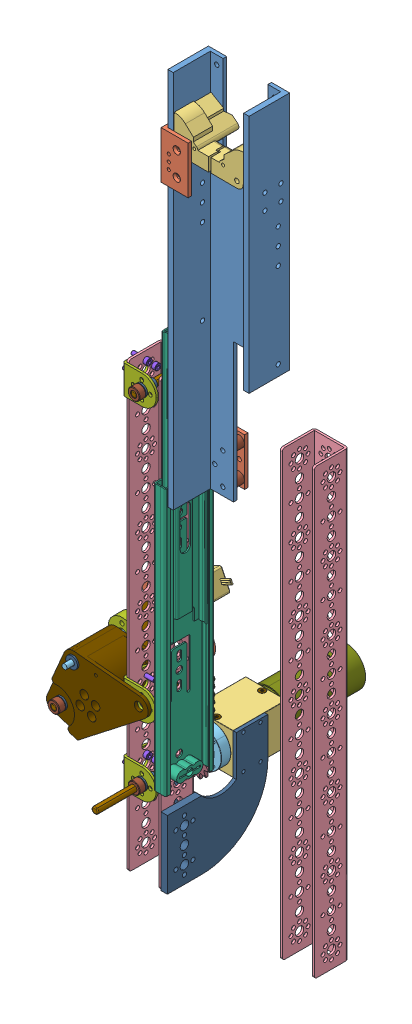
SolidWorks assembly 8699-18-203 Lander Latcher Assm, configuration Open. Lengths in mm.
Overall size (278.22 681.94 235.96).
117 component instances, 48 part files, 38 mates.
Components (placement in the parent):
- 1630T31 Machined U-Channel-1: 1630T31 Machined U-Channel [Default] at origin size (76.2 355.6 38.1)
- 8982K87 Machined Corner-1: 8982K87 Machined Corner [Default] at (-28.575 108.3632 3.175) x (0 0 -1) z (1 0 0) size (38.1 44.45 25.4)
- 8699-18-302 Lander Latcher Door-6: 8699-18-302 Lander Latcher Door [left] at (0.1845 135.2169 9.901) x (0.999933 -0.011604 0) z (0 0 1) size (32.43 32.42 38.5)
- 8699-18-302 Lander Latcher Door-7: 8699-18-302 Lander Latcher Door [right] at (0.1111 135.7078 9.901) x (-0.999976 0.006881 0) z (0 0 -1) size (32.43 32.42 38.5)
- 8699-18-204 Lander Latcher Drive-1: 8699-18-204 Lander Latcher Drive [Open] at (-72 -296.138 7.625) x (-1 0 0) z (0 0 -1) size (146.92 588.89 235.96)
  - tetrix_739069-2: tetrix_739069 [Default] at (0 192 32) x (1 0 0) z (0 1 0) size (32 32 416)
  - am-3643 NeveRest Sport, 104-1 with Motor-1: am-3643 NeveRest Sport, 104-1 with Motor [Default] at (37.7484 -95.467 21.4494) x (0 -1 0) z (0 0 1) size (48.85 48.85 145.31)
    - am-3643 NeveRest Sport, 104-1 with Motor(2)^am-3643 NeveRest Sport, 104-1 with Motor-1: am-3643 NeveRest Sport, 104-1 with Motor(2)^am-3643 NeveRest Sport, 104-1 with Motor [Default] at origin size (48.85 48.85 145.31) (virtual)
      - dv-XXXX Output Plug - 550 Sport^am-3643 NeveRest Sport, 104-1 with Motor(2)_am-3643 NeveRest Sport, 104-1 with Motor-1: dv-XXXX Output Plug - 550 Sport^am-3643 NeveRest Sport, 104-1 with Motor(2)_am-3643 NeveRest Sport, 104-1 with Motor [Default] at (30.7788 -45.9281 37.6212) x (-0.707107 -0.707107 0) z (0 0 1) size (34.54 34.54 34.87) (virtual)
        - dv-XXXX Output Plug with orbital bolt circle^dv-XXXX Output Plug - 550 Sport_am-3643 NeveRest Sport, 104-1 with Motor(2)_am-3643 NeveRest Sport, 104-1 with Motor-1: dv-XXXX Output Plug with orbital bolt circle^dv-XXXX Output Plug - 550 Sport_am-3643 NeveRest Sport, 104-1 with Motor(2)_am-3643 NeveRest Sport, 104-1 with Motor [Default] at (-7.0244 -4.5434 5.3964) size (34.54 34.54 17.78) (virtual)
        - BALL BEARING_5972K154^dv-XXXX Output Plug - 550 Sport_am-3643 NeveRest Sport, 104-1 with Motor(2)_am-3643 NeveRest Sport, 104-1 with Motor-1: BALL BEARING_5972K154^dv-XXXX Output Plug - 550 Sport_am-3643 NeveRest Sport, 104-1 with Motor(2)_am-3643 NeveRest Sport, 104-1 with Motor [Default] at (-7.0244 -4.5434 -0.8666) size (21 21 5) (virtual)
        - BALL BEARING_5972K154^dv-XXXX Output Plug - 550 Sport_am-3643 NeveRest Sport, 104-1 with Motor(2)_am-3643 NeveRest Sport, 104-1 with Motor-2: BALL BEARING_5972K154^dv-XXXX Output Plug - 550 Sport_am-3643 NeveRest Sport, 104-1 with Motor(2)_am-3643 NeveRest Sport, 104-1 with Motor [Default] at (-7.0244 -4.5434 10.1354) size (21 21 5) (virtual)
        - Nub Shaft^dv-XXXX Output Plug - 550 Sport_am-3643 NeveRest Sport, 104-1 with Motor(2)_am-3643 NeveRest Sport, 104-1 with Motor-1: Nub Shaft^dv-XXXX Output Plug - 550 Sport_am-3643 NeveRest Sport, 104-1 with Motor(2)_am-3643 NeveRest Sport, 104-1 with Motor [Default] at (-7.0244 -4.5434 20.2536) x (-0.939267 -0.343187 0) z (0.343187 -0.939267 0) size (19.05 34.87 19.05) (virtual)
      - dv-XXXX Carrier Stage 4-1 Planet, 5-1 Sun - 550 Sport^am-3643 NeveRest Sport, 104-1 with Motor(2)_am-3643 NeveRest Sport, 104-1 with Motor-1: dv-XXXX Carrier Stage 4-1 Planet, 5-1 Sun - 550 Sport^am-3643 NeveRest Sport, 104-1 with Motor(2)_am-3643 NeveRest Sport, 104-1 with Motor [Default] at (63.7059 -27.5277 100.4568) x (0.941837 -0.336071 0) z (-0.336071 -0.941837 0) size (29.23 15.47 28.59) (virtual)
        - am-2892+15T+pinion+3.2mm+bore^dv-XXXX Carrier Stage 4-1 Planet, 5-1 Sun - 550 Sport_am-3643 NeveRest Sport, 104-1 with Motor(2)_am-3643 NeveRest Sport, 104-1 with Motor-1: am-2892+15T+pinion+3.2mm+bore^dv-XXXX Carrier Stage 4-1 Planet, 5-1 Sun - 550 Sport_am-3643 NeveRest Sport, 104-1 with Motor(2)_am-3643 NeveRest Sport, 104-1 with Motor [Default] at (-25.9249 -17.3194 11.1026) x (0 -1 0) z (0.056322 0 -0.998413) size (5.31 10.12 10.18) (virtual)
        - am-2892+15T+pinion+3.2mm+bore^dv-XXXX Carrier Stage 4-1 Planet, 5-1 Sun - 550 Sport_am-3643 NeveRest Sport, 104-1 with Motor(2)_am-3643 NeveRest Sport, 104-1 with Motor-2: am-2892+15T+pinion+3.2mm+bore^dv-XXXX Carrier Stage 4-1 Planet, 5-1 Sun - 550 Sport_am-3643 NeveRest Sport, 104-1 with Motor(2)_am-3643 NeveRest Sport, 104-1 with Motor [Default] at (-16.9249 -17.3194 20.1026) x (0 -1 0) z (-0.169038 0 -0.98561) size (5.31 10.12 10.18) (virtual)
        - am-2892+15T+pinion+3.2mm+bore^dv-XXXX Carrier Stage 4-1 Planet, 5-1 Sun - 550 Sport_am-3643 NeveRest Sport, 104-1 with Motor(2)_am-3643 NeveRest Sport, 104-1 with Motor-3: am-2892+15T+pinion+3.2mm+bore^dv-XXXX Carrier Stage 4-1 Planet, 5-1 Sun - 550 Sport_am-3643 NeveRest Sport, 104-1 with Motor(2)_am-3643 NeveRest Sport, 104-1 with Motor [Default] at (-25.9249 -17.3194 29.1026) x (0 -1 0) z (-0.027474 0 -0.999623) size (5.31 10.12 10.18) (virtual)
        - am-2892+15T+pinion+3.2mm+bore^dv-XXXX Carrier Stage 4-1 Planet, 5-1 Sun - 550 Sport_am-3643 NeveRest Sport, 104-1 with Motor(2)_am-3643 NeveRest Sport, 104-1 with Motor-4: am-2892+15T+pinion+3.2mm+bore^dv-XXXX Carrier Stage 4-1 Planet, 5-1 Sun - 550 Sport_am-3643 NeveRest Sport, 104-1 with Motor(2)_am-3643 NeveRest Sport, 104-1 with Motor [Default] at (-34.9249 -17.3194 20.1026) x (0 -1 0) z (-0.064746 0 -0.997902) size (5.31 10.12 10.18) (virtual)
        - dv-XXXX - Carrier Plate 4-1 Planet, 5-1 Sun^dv-XXXX Carrier Stage 4-1 Planet, 5-1 Sun - 550 Sport_am-3643 NeveRest Sport, 104-1 with Motor(2)_am-3643 NeveRest Sport, 104-1 with Motor-1: dv-XXXX - Carrier Plate 4-1 Planet, 5-1 Sun^dv-XXXX Carrier Stage 4-1 Planet, 5-1 Sun - 550 Sport_am-3643 NeveRest Sport, 104-1 with Motor(2)_am-3643 NeveRest Sport, 104-1 with Motor [Default] at (-25.9249 -27.154 20.1026) size (25.04 10 25.04) (virtual)
        - 11T+pinion+3.2mm+bore^dv-XXXX Carrier Stage 4-1 Planet, 5-1 Sun - 550 Sport_am-3643 NeveRest Sport, 104-1 with Motor(2)_am-3643 NeveRest Sport, 104-1 with Motor-1: 11T+pinion+3.2mm+bore^dv-XXXX Carrier Stage 4-1 Planet, 5-1 Sun - 550 Sport_am-3643 NeveRest Sport, 104-1 with Motor(2)_am-3643 NeveRest Sport, 104-1 with Motor [Default] at (-25.9249 -22.6277 20.1026) x (0 -1 0) z (-0.988725 0 -0.149745) size (10 7.67 7.74) (virtual)
      - dv-XXXX Carrier Stage 5-1 Planet, 5-1 Sun^am-3643 NeveRest Sport, 104-1 with Motor(2)_am-3643 NeveRest Sport, 104-1 with Motor-1: dv-XXXX Carrier Stage 5-1 Planet, 5-1 Sun^am-3643 NeveRest Sport, 104-1 with Motor(2)_am-3643 NeveRest Sport, 104-1 with Motor [Default] at (6.8131 -34.6705 55.7021) x (-0.996841 0.079427 0) z (0.079427 0.996841 0) size (29.78 15.47 28.75) (virtual)
        - dv-XXXX - Carrier Plate 5-1 Planet, 5-1 Sun^dv-XXXX Carrier Stage 5-1 Planet, 5-1 Sun_am-3643 NeveRest Sport, 104-1 with Motor(2)_am-3643 NeveRest Sport, 104-1 with Motor-1: dv-XXXX - Carrier Plate 5-1 Planet, 5-1 Sun^dv-XXXX Carrier Stage 5-1 Planet, 5-1 Sun_am-3643 NeveRest Sport, 104-1 with Motor(2)_am-3643 NeveRest Sport, 104-1 with Motor [Default] at (-26.6144 7.6007 0.9439) size (25.04 10 25.04) (virtual)
        - 17T+pinion+3.2mm+bore^dv-XXXX Carrier Stage 5-1 Planet, 5-1 Sun_am-3643 NeveRest Sport, 104-1 with Motor(2)_am-3643 NeveRest Sport, 104-1 with Motor-1: 17T+pinion+3.2mm+bore^dv-XXXX Carrier Stage 5-1 Planet, 5-1 Sun_am-3643 NeveRest Sport, 104-1 with Motor(2)_am-3643 NeveRest Sport, 104-1 with Motor [Default] at (-35.0144 12.127 0.9439) x (0 1 0) z (-0.112997 0 0.993595) size (5.31 11.33 11.37) (virtual)
        - 17T+pinion+3.2mm+bore^dv-XXXX Carrier Stage 5-1 Planet, 5-1 Sun_am-3643 NeveRest Sport, 104-1 with Motor(2)_am-3643 NeveRest Sport, 104-1 with Motor-2: 17T+pinion+3.2mm+bore^dv-XXXX Carrier Stage 5-1 Planet, 5-1 Sun_am-3643 NeveRest Sport, 104-1 with Motor(2)_am-3643 NeveRest Sport, 104-1 with Motor [Default] at (-26.6144 12.127 9.3439) x (0 1 0) z (0.065842 0 0.99783) size (5.31 11.33 11.37) (virtual)
        - 17T+pinion+3.2mm+bore^dv-XXXX Carrier Stage 5-1 Planet, 5-1 Sun_am-3643 NeveRest Sport, 104-1 with Motor(2)_am-3643 NeveRest Sport, 104-1 with Motor-3: 17T+pinion+3.2mm+bore^dv-XXXX Carrier Stage 5-1 Planet, 5-1 Sun_am-3643 NeveRest Sport, 104-1 with Motor(2)_am-3643 NeveRest Sport, 104-1 with Motor [Default] at (-26.6144 12.127 -7.4561) x (0 1 0) z (0.038378 0 0.999263) size (5.31 11.33 11.37) (virtual)
        - 17T+pinion+3.2mm+bore^dv-XXXX Carrier Stage 5-1 Planet, 5-1 Sun_am-3643 NeveRest Sport, 104-1 with Motor(2)_am-3643 NeveRest Sport, 104-1 with Motor-4: 17T+pinion+3.2mm+bore^dv-XXXX Carrier Stage 5-1 Planet, 5-1 Sun_am-3643 NeveRest Sport, 104-1 with Motor(2)_am-3643 NeveRest Sport, 104-1 with Motor [Default] at (-18.2144 12.127 0.9439) x (0 1 0) z (0.205012 0 0.978759) size (5.31 11.33 11.37) (virtual)
        - 13T+pinion+3.2mm+bore^dv-XXXX Carrier Stage 5-1 Planet, 5-1 Sun_am-3643 NeveRest Sport, 104-1 with Motor(2)_am-3643 NeveRest Sport, 104-1 with Motor-1: 13T+pinion+3.2mm+bore^dv-XXXX Carrier Stage 5-1 Planet, 5-1 Sun_am-3643 NeveRest Sport, 104-1 with Motor(2)_am-3643 NeveRest Sport, 104-1 with Motor [Default] at (-26.6144 12.127 0.9439) x (0 -1 0) z (-0.984718 0 0.174154) size (10 8.9 8.96) (virtual)
      - dv-XXXX Carrier Stage 5-1 Planet, 0.3125 hex output^am-3643 NeveRest Sport, 104-1 with Motor(2)_am-3643 NeveRest Sport, 104-1 with Motor-1: dv-XXXX Carrier Stage 5-1 Planet, 0.3125 hex output^am-3643 NeveRest Sport, 104-1 with Motor(2)_am-3643 NeveRest Sport, 104-1 with Motor [Default] at (38.8348 -52.014 37.7173) x (0.574594 -0.818439 0) z (-0.818439 -0.574594 0) size (30.46 10 28.73) (virtual)
        - dv-XXXX - Carrier Plate 5-1 Planet, 0.3125 hex output^dv-XXXX Carrier Stage 5-1 Planet, 0.3125 hex output_am-3643 NeveRest Sport, 104-1 with Motor(2)_am-3643 NeveRest Sport, 104-1 with Motor-1: dv-XXXX - Carrier Plate 5-1 Planet, 0.3125 hex output^dv-XXXX Carrier Stage 5-1 Planet, 0.3125 hex output_am-3643 NeveRest Sport, 104-1 with Motor(2)_am-3643 NeveRest Sport, 104-1 with Motor [Default] at (-16.3468 15.5854 -4.8585) size (25.04 10 25.04) (virtual)
        - 17T+pinion+3.2mm+bore^dv-XXXX Carrier Stage 5-1 Planet, 0.3125 hex output_am-3643 NeveRest Sport, 104-1 with Motor(2)_am-3643 NeveRest Sport, 104-1 with Motor-1: 17T+pinion+3.2mm+bore^dv-XXXX Carrier Stage 5-1 Planet, 0.3125 hex output_am-3643 NeveRest Sport, 104-1 with Motor(2)_am-3643 NeveRest Sport, 104-1 with Motor [Default] at (-24.7468 20.1117 -4.8585) x (0 1 0) z (0.867721 0 0.497051) size (5.31 11.33 11.37) (virtual)
        - 17T+pinion+3.2mm+bore^dv-XXXX Carrier Stage 5-1 Planet, 0.3125 hex output_am-3643 NeveRest Sport, 104-1 with Motor(2)_am-3643 NeveRest Sport, 104-1 with Motor-2: 17T+pinion+3.2mm+bore^dv-XXXX Carrier Stage 5-1 Planet, 0.3125 hex output_am-3643 NeveRest Sport, 104-1 with Motor(2)_am-3643 NeveRest Sport, 104-1 with Motor [Default] at (-16.3468 20.1117 3.5415) x (0 1 0) z (-0.061129 0 0.99813) size (5.31 11.33 11.37) (virtual)
        - 17T+pinion+3.2mm+bore^dv-XXXX Carrier Stage 5-1 Planet, 0.3125 hex output_am-3643 NeveRest Sport, 104-1 with Motor(2)_am-3643 NeveRest Sport, 104-1 with Motor-3: 17T+pinion+3.2mm+bore^dv-XXXX Carrier Stage 5-1 Planet, 0.3125 hex output_am-3643 NeveRest Sport, 104-1 with Motor(2)_am-3643 NeveRest Sport, 104-1 with Motor [Default] at (-16.3468 20.1117 -13.2585) x (0 1 0) z (0.038378 0 0.999263) size (5.31 11.33 11.37) (virtual)
        - 17T+pinion+3.2mm+bore^dv-XXXX Carrier Stage 5-1 Planet, 0.3125 hex output_am-3643 NeveRest Sport, 104-1 with Motor(2)_am-3643 NeveRest Sport, 104-1 with Motor-4: 17T+pinion+3.2mm+bore^dv-XXXX Carrier Stage 5-1 Planet, 0.3125 hex output_am-3643 NeveRest Sport, 104-1 with Motor(2)_am-3643 NeveRest Sport, 104-1 with Motor [Default] at (-7.9468 20.1117 -4.8585) x (0 1 0) z (0.040503 0 0.999179) size (5.31 11.33 11.37) (virtual)
      - neveRest+15T+pinion^am-3643 NeveRest Sport, 104-1 with Motor(2)_am-3643 NeveRest Sport, 104-1 with Motor-1: neveRest+15T+pinion^am-3643 NeveRest Sport, 104-1 with Motor(2)_am-3643 NeveRest Sport, 104-1 with Motor [Default] at (-29.3619 -57.8483 143.121) x (-0.999543 0.030232 0) z (0 0 -1) size (38 38 89.79) (virtual)
        - am-3104 NeveRest Motor^neveRest+15T+pinion_am-3643 NeveRest Sport, 104-1 with Motor(2)_am-3643 NeveRest Sport, 104-1 with Motor-1: am-3104 NeveRest Motor^neveRest+15T+pinion_am-3643 NeveRest Sport, 104-1 with Motor(2)_am-3643 NeveRest Sport, 104-1 with Motor [Default] at (-61.259 21.9619 50.009) size (38 38 85.19) (virtual)
        - 15T+pinion+3.2mm+bore+motor^neveRest+15T+pinion_am-3643 NeveRest Sport, 104-1 with Motor(2)_am-3643 NeveRest Sport, 104-1 with Motor-1: 15T+pinion+3.2mm+bore+motor^neveRest+15T+pinion_am-3643 NeveRest Sport, 104-1 with Motor(2)_am-3643 NeveRest Sport, 104-1 with Motor [Default] at (-61.259 21.9619 54.7947) x (0 0 1) z (-0.930076 -0.367368 0) size (9.81 10.12 10.18) (virtual)
      - 91294A126_BLACK ALLOY STEEL FLAT-HEAD SOCKET CAP SCREW_91294A126^am-3643 NeveRest Sport, 104-1 with Motor(2)_am-3643 NeveRest Sport, 104-1 with Motor-1: 91294A126_BLACK ALLOY STEEL FLAT-HEAD SOCKET CAP SCREW_91294A126^am-3643 NeveRest Sport, 104-1 with Motor(2)_am-3643 NeveRest Sport, 104-1 with Motor [Default] at (13.433 -37.7484 46.9556) x (0 0 1) z (-1 0 0) size (6 6 6.01) (virtual)
      - Thrust Washer^am-3643 NeveRest Sport, 104-1 with Motor(2)_am-3643 NeveRest Sport, 104-1 with Motor-1: Thrust Washer^am-3643 NeveRest Sport, 104-1 with Motor(2)_am-3643 NeveRest Sport, 104-1 with Motor [Default] at (32.533 -37.7484 84.9184) x (0.422278 0.906466 0) z (0 0 -1) size (28.45 28.45 0.51) (virtual)
      - dv-XXXX Motor Mount Plug^am-3643 NeveRest Sport, 104-1 with Motor(2)_am-3643 NeveRest Sport, 104-1 with Motor-1: dv-XXXX Motor Mount Plug^am-3643 NeveRest Sport, 104-1 with Motor(2)_am-3643 NeveRest Sport, 104-1 with Motor [Default] at (32.533 -37.7484 93.1201) x (-0.707107 0.707107 0) z (0 0 -1) size (30.99 30.99 8.13) (virtual)
      - 91294A126_BLACK ALLOY STEEL FLAT-HEAD SOCKET CAP SCREW_91294A126^am-3643 NeveRest Sport, 104-1 with Motor(2)_am-3643 NeveRest Sport, 104-1 with Motor-2: 91294A126_BLACK ALLOY STEEL FLAT-HEAD SOCKET CAP SCREW_91294A126^am-3643 NeveRest Sport, 104-1 with Motor(2)_am-3643 NeveRest Sport, 104-1 with Motor [Default] at (32.533 -18.6484 89.5006) x (0.466078 0 0.884744) z (0 1 0) size (6 6 6.01) (virtual)
      - 91294A126_BLACK ALLOY STEEL FLAT-HEAD SOCKET CAP SCREW_91294A126^am-3643 NeveRest Sport, 104-1 with Motor(2)_am-3643 NeveRest Sport, 104-1 with Motor-3: 91294A126_BLACK ALLOY STEEL FLAT-HEAD SOCKET CAP SCREW_91294A126^am-3643 NeveRest Sport, 104-1 with Motor(2)_am-3643 NeveRest Sport, 104-1 with Motor [Default] at (32.533 -18.6484 46.9556) x (0.982767 0 0.184847) z (0 1 0) size (6 6 6.01) (virtual)
      - 91294A126_BLACK ALLOY STEEL FLAT-HEAD SOCKET CAP SCREW_91294A126^am-3643 NeveRest Sport, 104-1 with Motor(2)_am-3643 NeveRest Sport, 104-1 with Motor-4: 91294A126_BLACK ALLOY STEEL FLAT-HEAD SOCKET CAP SCREW_91294A126^am-3643 NeveRest Sport, 104-1 with Motor(2)_am-3643 NeveRest Sport, 104-1 with Motor [Default] at (13.433 -37.7484 89.5006) x (0 0 1) z (-1 0 0) size (6 6 6.01) (virtual)
      - 91294A126_BLACK ALLOY STEEL FLAT-HEAD SOCKET CAP SCREW_91294A126^am-3643 NeveRest Sport, 104-1 with Motor(2)_am-3643 NeveRest Sport, 104-1 with Motor-5: 91294A126_BLACK ALLOY STEEL FLAT-HEAD SOCKET CAP SCREW_91294A126^am-3643 NeveRest Sport, 104-1 with Motor(2)_am-3643 NeveRest Sport, 104-1 with Motor [Default] at (51.633 -37.7484 46.9556) x (0 -0.421523 0.906818) z (1 0 0) size (6 6 6.01) (virtual)
      - 91294A126_BLACK ALLOY STEEL FLAT-HEAD SOCKET CAP SCREW_91294A126^am-3643 NeveRest Sport, 104-1 with Motor(2)_am-3643 NeveRest Sport, 104-1 with Motor-6: 91294A126_BLACK ALLOY STEEL FLAT-HEAD SOCKET CAP SCREW_91294A126^am-3643 NeveRest Sport, 104-1 with Motor(2)_am-3643 NeveRest Sport, 104-1 with Motor [Default] at (51.633 -37.7484 89.5006) x (0 -0.712248 -0.701928) z (1 0 0) size (6 6 6.01) (virtual)
      - dv-XXXX - 3 Stage 550 Sport Ring Gear Housing^am-3643 NeveRest Sport, 104-1 with Motor(2)_am-3643 NeveRest Sport, 104-1 with Motor-1: dv-XXXX - 3 Stage 550 Sport Ring Gear Housing^am-3643 NeveRest Sport, 104-1 with Motor(2)_am-3643 NeveRest Sport, 104-1 with Motor [Default] at (13.483 -56.7984 68.2281) size (38.1 38.1 49.91) (virtual)
      - 10-32 x 0.25 Set Screw Cup Point^am-3643 NeveRest Sport, 104-1 with Motor(2)_am-3643 NeveRest Sport, 104-1 with Motor-1: 10-32 x 0.25 Set Screw Cup Point^am-3643 NeveRest Sport, 104-1 with Motor(2)_am-3643 NeveRest Sport, 104-1 with Motor [Default] at (42.0774 -42.1846 29.5006) x (-0.906832 0.421492 0) z (0.0498 0.107144 0.992995) size (6.35 4.83 4.83) (virtual)
      - M3x0.5x6mm SHCS_91290A111^am-3643 NeveRest Sport, 104-1 with Motor(2)_am-3643 NeveRest Sport, 104-1 with Motor-1: M3x0.5x6mm SHCS_91290A111^am-3643 NeveRest Sport, 104-1 with Motor(2)_am-3643 NeveRest Sport, 104-1 with Motor [Default] at (23.6942 -46.5873 96.1483) size (5.5 5.5 9.01) (virtual)
      - M3x0.5x6mm SHCS_91290A111^am-3643 NeveRest Sport, 104-1 with Motor(2)_am-3643 NeveRest Sport, 104-1 with Motor-2: M3x0.5x6mm SHCS_91290A111^am-3643 NeveRest Sport, 104-1 with Motor(2)_am-3643 NeveRest Sport, 104-1 with Motor [Default] at (41.3718 -28.9096 96.1483) size (5.5 5.5 9.01) (virtual)
  - 11435A110_SIDE-MOUNT DRAWER SLIDE-1: 11435A110_SIDE-MOUNT DRAWER SLIDE [Open] at (-21.6388 1.918 16) x (0 -1 0) z (-1 0 0) size (503.94 45.64 12.7)
  - Pitsco Education-739062-1: Pitsco Education-739062 [Default] at (-3.4747 191.2436 18.0384) x (0 -1 0) z (0 0 -1) size (27 31.5 31.5)
  - tetrix_739097-1: tetrix_739097 [Default] at (14 192 8) x (0 1 0) z (0 0 1) size (5.74 16.21 5.74)
  - tetrix_739097-2: tetrix_739097 [Default] at (14 200 16) x (0 1 0) z (0 0 1) size (5.74 16.21 5.74)
  - tetrix_739097-3: tetrix_739097 [Default] at (14 192 24) x (0 1 0) z (0 0 1) size (5.74 16.21 5.74)
  - tetrix_744708_6mm-1: tetrix_744708_6mm [Default] at (-41.9477 150.1357 -24.7204) size (6 5.5 100)
  - tetrix_739091-7: tetrix_739091 [Default] at (0 192 -3.4) x (1 0 0) z (0 -1 0) size (11 12.4 11)
  - tetrix_739091-8: tetrix_739091 [Default] at (0 192 33.4) x (0.999564 -0.029538 0) z (0.029538 0.999564 0) size (11 12.4 11)
  - tetrix_739092_collar-2: tetrix_739092_collar [Default] at (0 192 -6.5) size (11 11 6.2)
  - tetrix_739079_collar-2: tetrix_739079_collar [Default] at (0 192 44.65) size (22 22 9.5)
  - tetrix_739165-3: tetrix_739165 [Default] at (0 192 47.45) size (36 36 6.8)
  - tetrix_741665_6mm ID Plastic Bushing_Spacer-1: tetrix_741665_6mm ID Plastic Bushing_Spacer [Default] at (0 192 36.4) x (0.793594 -0.608447 0) z (0 0 1) size (9.4 9.4 3)
  - tetrix_741665_6mm ID Plastic Bushing_Spacer-2: tetrix_741665_6mm ID Plastic Bushing_Spacer [Default] at (0 192 34.9) x (-0.923728 -0.383049 0) z (0 0 -1) size (9.4 9.4 3)
  - tetrix_744708_6mm-2: tetrix_744708_6mm [Default] at (-41.9477 -169.8643 -61.3204) size (6 5.5 100)
  - Pitsco Education-739062-2: Pitsco Education-739062 [Default] at (-3.4747 -128.7564 18.0384) x (0 -1 0) z (0 0 -1) size (27 31.5 31.5)
  - tetrix_739091-9: tetrix_739091 [Default] at (0 -128 -3.4) x (-0.332615 -0.943063 0) z (-0.943063 0.332615 0) size (11 12.4 11)
  - tetrix_739091-10: tetrix_739091 [Default] at (0 -128 33.4) x (0.998296 -0.058356 0) z (0.058356 0.998296 0) size (11 12.4 11)
  - tetrix_739092_collar-3: tetrix_739092_collar [Default] at (0 -128 -6.5) size (11 11 6.2)
  - tetrix_739165-4: tetrix_739165 [Default] at (0 -128 44.65) x (-0.343187 0.939267 0) z (0 0 -1) size (36 36 6.8)
  - tetrix_739097-4: tetrix_739097 [Default] at (14 -128 24) x (0 1 0) z (0 0 1) size (5.74 16.21 5.74)
  - tetrix_739097-5: tetrix_739097 [Default] at (14 -120 16) x (0 1 0) z (0 0 1) size (5.74 16.21 5.74)
  - tetrix_739097-6: tetrix_739097 [Default] at (14 -128 8) x (0 1 0) z (0 0 1) size (5.74 16.21 5.74)
  - tetrix_739111_BHCS 6-32 x 0.375-1: tetrix_739111_BHCS 6-32 x 0.375 [92949A146] at (-7.5141 -130.7455 38.7958) x (-0.923728 -0.383049 0) z (0 0 -1) size (6.65 6.65 11.49)
  - tetrix_739111_BHCS 6-32 x 0.375-2: tetrix_739111_BHCS 6-32 x 0.375 [92949A146] at (7.5141 -125.2545 38.7958) x (-0.923728 -0.383049 0) z (0 0 -1) size (6.65 6.65 11.49)
  - tetrix_739097-7: tetrix_739097 [Default] at (-2.7455 -120.4859 40.65) x (0.975434 -0.220292 0) z (0.220292 0.975434 0) size (5.74 16.21 5.74)
  - tetrix_39173_outside_link-1: tetrix_39173_outside_link [Default] at (-14.7363 191.7562 46.05) x (0 1 0) z (0 0 1) size (11.43 5.08 7.82)
  - tetrix_39173_outside_link-2: tetrix_39173_outside_link [Default] at (-14.7363 -63.2855 46.05) x (0 -1 0) z (0 0 1) size (11.43 5.08 7.82)
  - tetrix_39173_outside_link-3: tetrix_39173_outside_link [Default] at (-14.7363 -75.9855 46.05) x (0 -1 0) z (0 0 1) size (11.43 5.08 7.82)
  - tetrix_39173_outside_link-4: tetrix_39173_outside_link [Default] at (-14.7363 -88.6855 46.05) x (0 -1 0) z (0 0 1) size (11.43 5.08 7.82)
  - tetrix_39173_inside_link-1: tetrix_39173_inside_link [Default] at (-14.7363 -69.6355 46.05) x (0 -1 0) z (0 0 1) size (11.43 5.08 4.9)
  - tetrix_39173_inside_link-2: tetrix_39173_inside_link [Default] at (-14.7363 -82.3355 46.05) x (0 -1 0) z (0 0 1) size (11.43 5.08 4.9)
  - 8699-18-205 Lander Latcher Drive Adj-1: 8699-18-205 Lander Latcher Drive Adj [Default] at (0 -64 15) x (0.899951 -0.435991 0) z (0 0 1) size (116.51 74.65 143.2)
    - 8699-18-364 Lock Adjustment Plate-1: 8699-18-364 Lock Adjustment Plate [Default] at origin size (108.78 66.42 40)
    - tetrix_739107_32mm_standoff-1: tetrix_739107_32mm_standoff [Default] at (80.8213 0.0145 47.7605) size (7.16 6.2 32)
    - tetrix_741789-1: tetrix_741789 [Default] at (52.7846 32 86) x (1 0 0) z (0 0 -1) size (59.8 60.75 2)
    - tetrix_739197_servo-1: tetrix_739197_servo [Default] at (52.7846 32 88.5) x (0 1 0) z (-1 0 0) size (20 43.2 56.6)
    - tetrix_739278_axle_adapter-1: tetrix_739278_axle_adapter [Default] at (52.7846 32 75.2) x (0.998477 0.055163 0) z (0 0 -1) size (16 16 23)
    - tetrix_739088-1: tetrix_739088 [Default] at (52.7846 32 21.9) x (-0.87123 0.490874 0) z (0 0 -1) size (4.73 4.46 100)
    - tetrix_744708_6mm-2: tetrix_744708_6mm [Default] at (92.5192 -58.7572 -38.7204) x (0.607985 0.793949 0) z (0 0 1) size (6 5.5 100)
    - tetrix_739091-1: tetrix_739091 [Default] at (52.7846 32 -21.4) x (1 0 0) z (0 -1 0) size (11 12.4 11)
    - tetrix_739091-2: tetrix_739091 [Default] at (84.7846 0 21.4) x (-0.82449 0.565877 0) z (-0.565877 -0.82449 0) size (11 12.4 11)
    - tetrix_739091-3: tetrix_739091 [Default] at (84.7846 0 -17.4) x (-0.539749 -0.841826 0) z (-0.841826 0.539749 0) size (11 12.4 11)
    - tetrix_739079_collar-1: tetrix_739079_collar [Default] at (84.7846 0 36.45) x (0.312774 0.949828 0) z (0 0 -1) size (22 22 9.5)
    - tetrix_739165-1: tetrix_739165 [Default] at (84.7846 0 32.45) x (-0.312774 -0.949828 0) z (0 0 1) size (36 36 6.8)
    - tetrix_739065-2: tetrix_739065 [Default] at (36.7846 0 36) x (0 0 1) z (0 1 0) size (32 32 32)
    - tetrix_739091-4: tetrix_739091 [Default] at (52.7846 32 21.4) x (-0.923728 -0.383049 0) z (0.383049 -0.923728 0) size (11 12.4 11)
    - tetrix_739097-1: tetrix_739097 [Default] at (44.7846 0 17) x (0.933008 0.359855 0) z (-0.359855 0.933008 0) size (5.74 16.21 5.74)
    - tetrix_739097-2: tetrix_739097 [Default] at (52.7846 -8 17) x (0.058002 0.998316 0) z (-0.998316 0.058002 0) size (5.74 16.21 5.74)
    - 8699-18-366 Lock-1: 8699-18-366 Lock [Default] at (52.7846 32 31.05) x (0.909547 0.415601 0) z (0 0 1) size (26 57.92 10)
    - tetrix_739097-3: tetrix_739097 [Default] at (69.3764 -4.3113 26.05) x (-0.975108 0.22173 0) z (-0.22173 -0.975108 0) size (5.74 16.21 5.74)
    - tetrix_739172_collar-1: tetrix_739172_collar [Default] at (52.7846 32 36.05) x (-0.909547 -0.415601 0) z (0 0 -1) size (22.1 22.1 9.5)
    - tetrix_739092_collar-1: tetrix_739092_collar [Default] at (84.7846 0 -20.5) x (0.871034 0.491223 0) z (0 0 1) size (11 11 6.2)
    - tetrix_739092_collar-2: tetrix_739092_collar [Default] at (84.7846 0 24.5) x (0.871034 0.491223 0) z (0 0 1) size (11 11 6.2)
  - Pitsco Education-739062-3: Pitsco Education-739062 [Default] at (-3.4747 -64.7564 18.0384) x (0 -1 0) z (0 0 -1) size (27 31.5 31.5)
  - tetrix_739097-8: tetrix_739097 [Default] at (18 -56 16) x (0 0.381849 -0.924225) z (0 -0.924225 -0.381849) size (5.74 16.21 5.74)
  - tetrix_739097-9: tetrix_739097 [Default] at (18 -64 8) x (0 -1 0) z (0 0 1) size (5.74 16.21 5.74)
  - tetrix_739097-10: tetrix_739097 [Default] at (18 -64 24) x (0 -1 0) z (0 0 1) size (5.74 16.21 5.74)
  - tetrix_739097-13: tetrix_739097 [Default] at (18 -72 16) x (0 1 0) z (0 0 -1) size (5.74 16.21 5.74)
  - 8699-18-365 Lock Adjustment Reinforcement-1: 8699-18-365 Lock Adjustment Reinforcement [Default] at (40.062 -58.4877 35) x (0.333979 -0.94258 0) z (-0.94258 -0.333979 0) size (117 6 30)
  - 8699-18-369 LL Motor Mount 1-1: 8699-18-369 LL Motor Mount 1 [Default] at (-19.05 -160 16) x (0 0 1) z (0 -1 0) size (94.18 38.05 99.05)
- tetrix_739069-4: tetrix_739069 [Default] at (72 -104.138 -24.375) x (-1 0 0) z (0 1 0) size (32 32 416)
- 8982K87 Machined Corner-2: 8982K87 Machined Corner [Default] at (-35.385 -155.575 -43.9) x (1 0 0) z (0 0 -1) size (38.1 44.45 25.4)
- 8699-18-371 LL Chain Mount Spacer-1: 8699-18-371 LL Chain Mount Spacer [Default] at (-21.335 -140.85 -25.1) x (1 0 0) z (0 -1 0) size (10 12.1 10)
- 8699-18-371 LL Chain Mount Spacer-2: 8699-18-371 LL Chain Mount Spacer [Default] at (-28.835 -155.575 -25.1) x (1 0 0) z (0 -1 0) size (10 12.1 10)
- 8699-18-371 LL Chain Mount Spacer-3: 8699-18-371 LL Chain Mount Spacer [Default] at (-21.335 -170.3 -25.1) x (1 0 0) z (0 -1 0) size (10 12.1 10)
- 8699-18-372 LL Slide Mount Spacer-1: 8699-18-372 LL Slide Mount Spacer [Default] at (-40.65 74.5851 -8.375) x (0 -1 0) z (0 0 1) size (10 5.1 10)
- 8699-18-372 LL Slide Mount Spacer-2: 8699-18-372 LL Slide Mount Spacer [Default] at (-40.65 58.5851 -8.375) x (0 -1 0) z (0 0 1) size (10 5.1 10)
- 8699-18-372 LL Slide Mount Spacer-3: 8699-18-372 LL Slide Mount Spacer [Default] at (-40.65 42.5851 -8.375) x (0 -1 0) z (0 0 1) size (10 5.1 10)
- 8699-18-372 LL Slide Mount Spacer-4: 8699-18-372 LL Slide Mount Spacer [Default] at (-40.65 -37.4269 -8.375) x (0 -1 0) z (0 0 1) size (10 5.1 10)
Mates (geometry in assembly coordinates):
- Coincident80: coordinate: point of 1630T31 Machined U-Channel-1; point of assembly
- Coincident81: coincident: plane of 1630T31 Machined U-Channel-1 through (-38.1 177.8 19.05) normal (0 0 1); plane of 8982K87 Machined Corner-1 through (-15.875 130.5882 19.05) normal (0 0 -1)
- Coincident82: coincident: plane of 1630T31 Machined U-Channel-1 through (-38.1 177.8 19.05) normal (-1 0 0); plane of 8982K87 Machined Corner-1 through (-38.1 130.5882 19.05) normal (1 0 0)
- Coincident83: coincident: plane of 8982K87 Machined Corner-1 through (-15.875 130.5882 19.05) normal (0 0 -1); plane of ? through (-4.6188 113.6499 19.05) normal (0 0 1)
- Concentric82: concentric: cylinder of 8982K87 Machined Corner-1 through (-26.52 119.4757 22.225) axis (0 0 1) radius 1.8986; cylinder of ? through (-26.52 119.4757 1.05) axis (0 0 1) radius 2
- Concentric83: concentric: cylinder of 1630T31 Machined U-Channel-1 through (-26.52 119.4757 -19.05) axis (0 0 1) radius 2; cylinder of ? through (-26.52 119.4757 1.05) axis (0 0 1) radius 2
- Concentric84: concentric: cylinder of 8982K87 Machined Corner-1 through (-26.52 119.4757 22.225) axis (0 0 1) radius 1.8986; cylinder of 8699-18-302 Lander Latcher Door-6 through (-26.52 119.4757 -19.599) axis (0 0 1) radius 2.1
- Width1: width: plane of 8699-18-302 Lander Latcher Door-6 through (-26.52 119.4757 18.901) normal (0 0 1); plane of 8699-18-302 Lander Latcher Door-6 through (-26.52 119.4757 -15.599) normal (0 0 -1); plane of 8982K87 Machined Corner-1 through (-15.875 130.5882 19.05) normal (0 0 -1); plane of 1630T31 Machined U-Channel-1 through (-33.02 177.8 -15.748) normal (0 0 1)
- Concentric85: concentric: cylinder of 1630T31 Machined U-Channel-1 through (-26.52 119.4757 -19.05) axis (0 0 1) radius 2; cylinder of 8982K87 Machined Corner-1 through (-26.52 119.4757 22.225) axis (0 0 1) radius 1.8986
- Concentric86: concentric: cylinder of 1630T31 Machined U-Channel-1 through (26.52 119.4757 -19.05) axis (0 0 1) radius 2; cylinder of 8699-18-302 Lander Latcher Door-7 through (26.52 119.4757 18.901) axis (0 0 -1) radius 2.1
- Coincident84: coincident: plane of 8699-18-302 Lander Latcher Door-6 through (-26.52 119.4757 18.901) normal (0 0 1); plane of 8699-18-302 Lander Latcher Door-7 through (26.52 119.4757 18.901) normal (0 0 1)
- Coincident85: coincident: plane of 1630T31 Machined U-Channel-1 through (-38.1 177.8 19.05) normal (-1 0 0); plane of 8699-18-204 Lander Latcher Drive-1/11435A110_SIDE-MOUNT DRAWER SLIDE-1 through (-38.1 -165.188 -8.375) normal (1 0 0)
- Distance1: distance = 5 mm: plane of 8699-18-204 Lander Latcher Drive-1/tetrix_739092_collar-2 through (-77.5 -104.138 17.225) normal (0 0 1); plane of 8982K87 Machined Corner-1 through (-15.875 130.5882 22.225) normal (0 0 1)
- Distance2: distance = 93.052 mm: plane of 8699-18-204 Lander Latcher Drive-1/11435A110_SIDE-MOUNT DRAWER SLIDE-1 through (-44.951 84.748 -17.265) normal (0 1 0); plane of 1630T31 Machined U-Channel-1 through (0 177.8 0) normal (0 1 0)
- Coincident88: coincident: plane of 8699-18-204 Lander Latcher Drive-1/tetrix_739069-2 through (-88 -104.138 -24.375) normal (-1 0 0); line of assembly
- Coincident89: coincident: plane of 8699-18-204 Lander Latcher Drive-1/tetrix_739069-2 through (-88 -504.138 -24.375) normal (0 0 -1); plane of tetrix_739069-4 through (56 -504.138 -24.375) normal (0 0 -1)
- Coincident90: coincident: plane of 8699-18-204 Lander Latcher Drive-1/tetrix_739069-2 through (-88 -88.138 -24.375) normal (0 1 0); plane of tetrix_739069-4 through (56 -88.138 -24.375) normal (0 1 0)
- Coincident91: coincident: plane of tetrix_739069-4 through (88 -104.138 -24.375) normal (1 0 0); line of assembly
- Coincident92: coincident: plane of 1630T31 Machined U-Channel-1 through (-38.1 177.8 -19.05) normal (0 0 -1); plane of 8982K87 Machined Corner-2 through (-17.9 -133.35 -19.05) normal (0 0 1)
- Coincident93: coincident: plane of 8699-18-204 Lander Latcher Drive-1/11435A110_SIDE-MOUNT DRAWER SLIDE-1 through (-43.3 -165.188 -8.375) normal (1 0 0); plane of 8982K87 Machined Corner-2 through (-43.3 -133.35 -19.05) normal (-1 0 0)
- Coincident94: coincident: plane of 1630T31 Machined U-Channel-1 through (0 -177.8 0) normal (0 -1 0); plane of 8982K87 Machined Corner-2
- Distance3: distance = 12.15 mm: plane of 8982K87 Machined Corner-2 through (-54.435 -177.8 -31.2) normal (0 0 1); plane of 1630T31 Machined U-Channel-1 through (-38.1 177.8 -19.05) normal (0 0 -1)
- Coincident96: coincident: plane of 1630T31 Machined U-Channel-1 through (0 -177.8 0) normal (0 -1 0); plane of 8982K87 Machined Corner-2 through (-35.385 -177.8 -43.9) normal (0 -1 0)
- Coincident97: coincident: line of 8699-18-204 Lander Latcher Drive-1 through (-54.435 -424.138 -38.425) axis (0 1 0); plane of 8982K87 Machined Corner-2 through (-54.435 -177.8 -56.6) normal (-1 0 0)
- Concentric87: concentric: cylinder of 1630T31 Machined U-Channel-1 through (-21.335 -140.85 -19.05) axis (0 0 1) radius 2; cylinder of 8699-18-371 LL Chain Mount Spacer-1 through (-21.335 -140.85 -19.05) axis (0 0 -1) radius 2
- Coincident98: coincident: plane of 1630T31 Machined U-Channel-1 through (-38.1 177.8 -19.05) normal (0 0 -1); plane of 8699-18-371 LL Chain Mount Spacer-1 through (-21.335 -140.85 -19.05) normal (0 0 1)
- Coincident99: coincident: plane of 1630T31 Machined U-Channel-1 through (-38.1 177.8 -19.05) normal (0 0 -1); plane of 8699-18-371 LL Chain Mount Spacer-2 through (-28.835 -155.575 -19.05) normal (0 0 1)
- Coincident100: coincident: plane of 1630T31 Machined U-Channel-1 through (-38.1 177.8 -19.05) normal (0 0 -1); plane of 8699-18-371 LL Chain Mount Spacer-3 through (-21.335 -170.3 -19.05) normal (0 0 1)
- Concentric88: concentric: cylinder of 1630T31 Machined U-Channel-1 through (-21.335 -170.3 -19.05) axis (0 0 1) radius 2; cylinder of 8699-18-371 LL Chain Mount Spacer-3 through (-21.335 -170.3 -19.05) axis (0 0 -1) radius 2
- Concentric89: concentric: cylinder of 1630T31 Machined U-Channel-1 through (-28.835 -155.575 -19.05) axis (0 0 1) radius 2; cylinder of 8699-18-371 LL Chain Mount Spacer-2 through (-28.835 -155.575 -19.05) axis (0 0 -1) radius 2
- Coincident101: coincident: plane of 1630T31 Machined U-Channel-1 through (-38.1 177.8 19.05) normal (-1 0 0); plane of 8699-18-372 LL Slide Mount Spacer-1 through (-38.1 74.5851 -8.375) normal (1 0 0)
- Coincident102: coincident: plane of 1630T31 Machined U-Channel-1 through (-38.1 177.8 19.05) normal (-1 0 0); plane of 8699-18-372 LL Slide Mount Spacer-2 through (-38.1 58.5851 -8.375) normal (1 0 0)
- Coincident103: coincident: plane of 1630T31 Machined U-Channel-1 through (-38.1 177.8 19.05) normal (-1 0 0); plane of 8699-18-372 LL Slide Mount Spacer-3 through (-38.1 42.5851 -8.375) normal (1 0 0)
- Coincident104: coincident: plane of 1630T31 Machined U-Channel-1 through (-38.1 177.8 19.05) normal (-1 0 0); plane of 8699-18-372 LL Slide Mount Spacer-4 through (-38.1 -37.4269 -8.375) normal (1 0 0)
- Concentric90: concentric: cylinder of 1630T31 Machined U-Channel-1 through (38.1 74.5851 -8.375) axis (-1 0 0) radius 2; cylinder of 8699-18-372 LL Slide Mount Spacer-1 through (-38.1 74.5851 -8.375) axis (-1 0 0) radius 2
- Concentric91: concentric: cylinder of 1630T31 Machined U-Channel-1 through (38.1 58.5851 -8.375) axis (-1 0 0) radius 2; cylinder of 8699-18-372 LL Slide Mount Spacer-2 through (-38.1 58.5851 -8.375) axis (-1 0 0) radius 2
- Concentric92: concentric: cylinder of 1630T31 Machined U-Channel-1 through (38.1 42.5851 -8.375) axis (-1 0 0) radius 2; cylinder of 8699-18-372 LL Slide Mount Spacer-3 through (-38.1 42.5851 -8.375) axis (-1 0 0) radius 2
- Concentric93: concentric: cylinder of 1630T31 Machined U-Channel-1 through (38.1 -37.4269 -8.375) axis (-1 0 0) radius 2; cylinder of 8699-18-372 LL Slide Mount Spacer-4 through (-38.1 -37.4269 -8.375) axis (-1 0 0) radius 2
